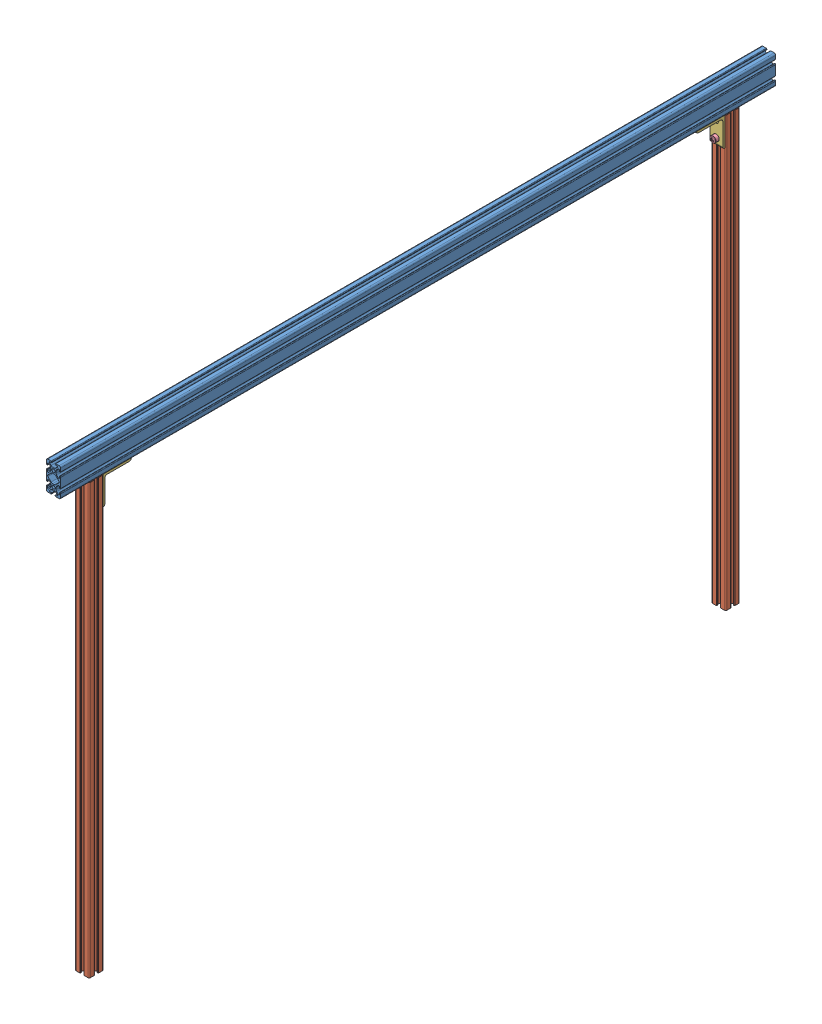
SolidWorks assembly ExampleAssembly_Casper, configuration Default. Lengths in mm.
Overall size (20 639.98 1000).
13 component instances, 5 part files, 30 mates.
Components (placement in the parent):
- ST_8020_DoubleRail-2: ST_8020_DoubleRail [1000mm] x (0 1 0) z (0 0 1) size (39.98 19.99 1000)
- ST_8020_SingleRail-2: ST_8020_SingleRail [600mm] at (0 -319.9898 450) x (-1 0 0) z (0 1 0) size (20 20 600)
- MT_CornerBracket_Extended-1: MT_CornerBracket_Extended [5537T441] at (0 -19.9898 440) x (0 0 -1) z (-1 0 0) size (40 40 18)
- MT_T-slot_bolt-1: MT_T-slot_bolt [91290A222] at (0 -49.9898 438.5) x (1 0 0) z (0 0 -1) size (8.5 8.5 13.23)
- MT_T-slot_nut-2: MT_T-slot_nut [5537T651] at (0 -49.9898 442.9754) x (0 1 0) z (0 0 1) size (15 8 3)
- MT_T-slot_nut-3: MT_T-slot_nut [5537T651] at (0 -17.2864 410) x (0 0 -1) z (0 1 0) size (15 8 3)
- MT_T-slot_bolt-2: MT_T-slot_bolt [91290A222] at (0 -21.4898 410) x (0.930301 0 -0.366796) z (0 -1 0) size (8.5 8.5 13.23)
- MT_CornerBracket_Extended-2: MT_CornerBracket_Extended [5537T441] at (0 -19.9898 -430) x (0 0 1) z (1 0 0) size (40 40 18)
- MT_T-slot_bolt-4: MT_T-slot_bolt [91290A222] at (0 -49.9898 -428.5) x (0.923728 0.383049 0) z (0 0 1) size (8.5 8.5 13.23)
- MT_T-slot_nut-5: MT_T-slot_nut [5537T651] at (0 -49.9898 -432.9754) x (0 -1 0) z (0 0 -1) size (15 8 3)
- MT_T-slot_nut-6: MT_T-slot_nut [5537T651] at (0 -17.2864 -400) x (0 0 -1) z (0 1 0) size (15 8 3)
- MT_T-slot_bolt-5: MT_T-slot_bolt [91290A222] at (0 -21.4898 -400) x (0.844507 0 -0.535544) z (0 -1 0) size (8.5 8.5 13.23)
- ST_8020_SingleRail-3: ST_8020_SingleRail [600mm] at (0 -319.9898 -440) x (-1 0 0) z (0 1 0) size (20 20 600)
Mates (geometry in assembly coordinates):
- Coincident1: coincident anti-aligned: plane of ST_8020_SingleRail-2 through (-3 -19.9898 442.0754) normal (0 0 1); plane of MT_T-slot_nut-2 through (0 -50.9898 442.0754) normal (0 0 -1)
- Coincident2: coincident aligned: plane of ST_8020_SingleRail-2 through (0 -319.9898 450) normal (-1 0 0); plane of MT_T-slot_nut-2 through (0 -49.9898 442.9754) normal (-1 0 0)
- Concentric1: concentric anti-aligned: cylinder of MT_T-slot_bolt-1 through (0 -49.9898 445) axis (0 0 1) radius 2.5; cylinder of MT_T-slot_nut-2 through (0 -49.9898 445.0754) axis (0 0 -1) radius 2.5
- Coincident3: coincident anti-aligned: plane of MT_CornerBracket_Extended-1 through (-9 -56.9898 437) normal (0 0 -1); plane of MT_T-slot_bolt-1 through (0 -53.9898 437) normal (0 0 1)
- Coincident4: coincident anti-aligned: plane of ST_8020_SingleRail-2 through (3 -19.9898 440) normal (0 0 -1); plane of MT_CornerBracket_Extended-1 through (-9 -19.9898 440) normal (0 0 1)
- Coincident5: coincident anti-aligned: plane of ST_8020_DoubleRail-2 through (7.9883 -19.9898 500) normal (0 -1 0); plane of ST_8020_SingleRail-2 through (-3 -19.9898 440.5) normal (0 1 0)
- Coincident6: coincident anti-aligned: plane of ST_8020_DoubleRail-2 through (7.9883 -19.9898 500) normal (0 -1 0); plane of MT_CornerBracket_Extended-1 through (-9 -19.9898 400) normal (0 1 0)
- Concentric2: concentric aligned: cylinder of MT_CornerBracket_Extended-1 through (0 -49.9898 400) axis (0 0 1) radius 2.75; cylinder of MT_T-slot_bolt-1 through (0 -49.9898 445) axis (0 0 1) radius 2.5
- Concentric3: concentric anti-aligned: cylinder of MT_T-slot_nut-3 through (0 -15.1864 410) axis (0 -1 0) radius 2.5; cylinder of MT_T-slot_bolt-2 through (0 -14.9898 410) axis (0 1 0) radius 2.5
- Coincident7: coincident anti-aligned: plane of ST_8020_DoubleRail-2 through (-4.9149 -18.1864 500) normal (0 1 0); plane of MT_T-slot_nut-3 through (0 -18.1864 411) normal (0 -1 0)
- Coincident8: coincident aligned: plane of ST_8020_DoubleRail-2 through (0 0 0) normal (-1 0 0); plane of MT_T-slot_nut-3 through (0 -17.2864 410) normal (-1 0 0)
- Coincident9: coincident anti-aligned: plane of MT_CornerBracket_Extended-1 through (-9 -22.9898 434) normal (0 -1 0); plane of MT_T-slot_bolt-2 through (1.4672 -22.9898 413.7212) normal (0 1 0)
- Concentric4: concentric aligned: cylinder of MT_CornerBracket_Extended-1 through (0 -59.9898 410) axis (0 1 0) radius 2.75; cylinder of MT_T-slot_bolt-2 through (0 -14.9898 410) axis (0 1 0) radius 2.5
- Coincident10: coincident aligned: plane of ST_8020_DoubleRail-2 through (0 0 0) normal (-1 0 0); plane of ST_8020_SingleRail-2 through (0 -319.9898 450) normal (-1 0 0)
- Coincident11: coincident anti-aligned: plane of MT_T-slot_nut-5 through (0 -48.9898 -432.0754) normal (0 0 1); plane of ST_8020_SingleRail-3 through (-3 -19.9898 -432.0754) normal (0 0 -1)
- Coincident12: coincident aligned: plane of MT_T-slot_nut-5 through (0 -49.9898 -432.9754) normal (-1 0 0); plane of ST_8020_SingleRail-3 through (0 -319.9898 -440) normal (-1 0 0)
- Concentric6: concentric anti-aligned: cylinder of MT_T-slot_bolt-4 through (0 -49.9898 -435) axis (0 0 -1) radius 2.5; cylinder of MT_T-slot_nut-5 through (0 -49.9898 -435.0754) axis (0 0 1) radius 2.5
- Coincident13: coincident anti-aligned: plane of MT_CornerBracket_Extended-2 through (9 -56.9898 -427) normal (0 0 1); plane of MT_T-slot_bolt-4 through (-1.5322 -46.2949 -427) normal (0 0 -1)
- Coincident14: coincident anti-aligned: plane of MT_CornerBracket_Extended-2 through (9 -19.9898 -430) normal (0 0 -1); plane of ST_8020_SingleRail-3 through (3 -19.9898 -430) normal (0 0 1)
- Concentric7: concentric aligned: cylinder of MT_CornerBracket_Extended-2 through (0 -49.9898 -390) axis (0 0 -1) radius 2.75; cylinder of MT_T-slot_bolt-4 through (0 -49.9898 -435) axis (0 0 -1) radius 2.5
- Concentric8: concentric anti-aligned: cylinder of MT_T-slot_nut-6 through (0 -15.1864 -400) axis (0 -1 0) radius 2.5; cylinder of MT_T-slot_bolt-5 through (0 -14.9898 -400) axis (0 1 0) radius 2.5
- Coincident15: coincident anti-aligned: plane of MT_CornerBracket_Extended-2 through (9 -22.9898 -424) normal (0 -1 0); plane of MT_T-slot_bolt-5 through (2.1422 -22.9898 -396.622) normal (0 1 0)
- Concentric9: concentric aligned: cylinder of MT_CornerBracket_Extended-2 through (0 -59.9898 -400) axis (0 1 0) radius 2.75; cylinder of MT_T-slot_bolt-5 through (0 -14.9898 -400) axis (0 1 0) radius 2.5
- Coincident17: coincident anti-aligned: plane of ST_8020_DoubleRail-2 through (7.9883 -19.9898 500) normal (0 -1 0); plane of MT_CornerBracket_Extended-2 through (9 -19.9898 -390) normal (0 1 0)
- Coincident18: coincident anti-aligned: plane of ST_8020_DoubleRail-2 through (-4.9149 -18.1864 500) normal (0 1 0); plane of MT_T-slot_nut-6 through (0 -18.1864 -399) normal (0 -1 0)
- Coincident19: coincident aligned: plane of ST_8020_DoubleRail-2 through (0 0 0) normal (-1 0 0); plane of MT_T-slot_nut-6 through (0 -17.2864 -400) normal (-1 0 0)
- Coincident20: coincident aligned: plane of ST_8020_DoubleRail-2 through (0 0 0) normal (-1 0 0); plane of ST_8020_SingleRail-3 through (0 -319.9898 -440) normal (-1 0 0)
- Coincident22: coincident anti-aligned: plane of ST_8020_DoubleRail-2 through (7.9883 -19.9898 500) normal (0 -1 0); plane of ST_8020_SingleRail-3 through (-3 -19.9898 -449.5) normal (0 1 0)
- Distance2: distance = 50 mm aligned: plane of ST_8020_SingleRail-2 through (0 -319.9898 450) normal (0 0 1); plane of ST_8020_DoubleRail-2 through (-6.6251 -11.1283 500) normal (0 0 1)
- Distance3: distance = 50 mm aligned: plane of ST_8020_DoubleRail-2 through (-6.6251 -11.1283 -500) normal (0 0 -1); plane of ST_8020_SingleRail-3 through (3 -19.9898 -450) normal (0 0 -1)
